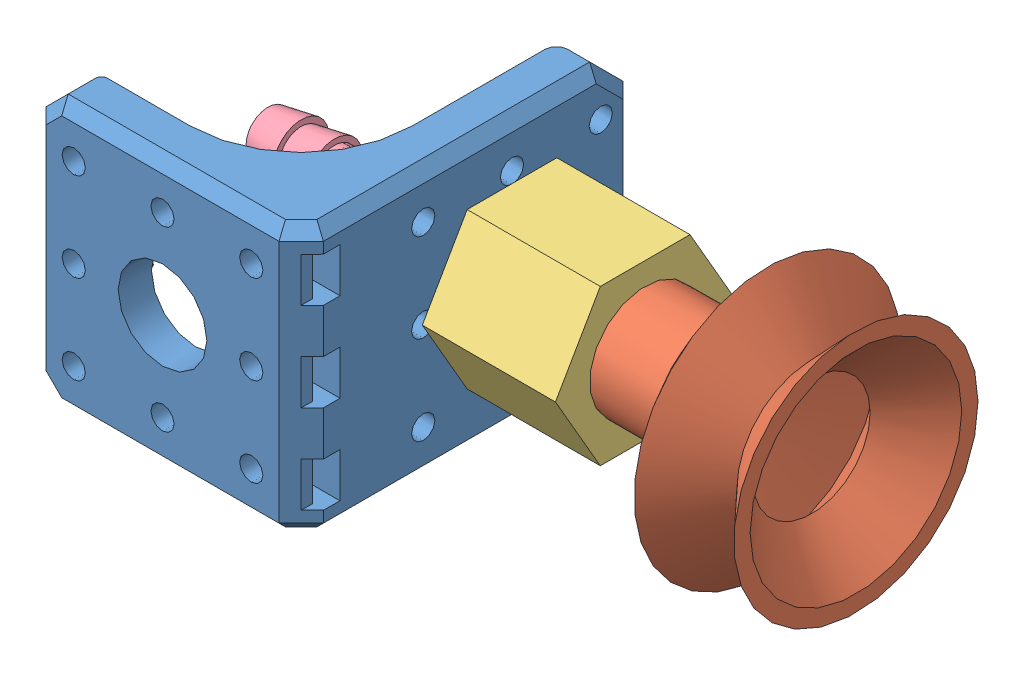
SolidWorks assembly Assemblage1, configuration Défaut. Lengths in mm.
Overall size (55 24 31).
4 component instances, 4 part files, 6 mates.
Components (placement in the parent):
- F9ORG-1: F9ORG [Défaut] at (9.7054 -0.548 15) size (24 24 30)
- ventouse_coval_VSA22_M5-1: ventouse_coval_VSA22_M5 [Default] at (40.7054 -0.548 -4) x (0 1 0) z (0 0 1) size (24 19 24)
- Insert_Femelle_IF10A-1: Insert_Femelle_IF10A [Défaut] at (21.7054 -0.548 -4) x (0 1 0) z (0 0 1) size (14 20 16.17)
- cannule_male_TET1804-1: cannule_male_TET1804 [Défaut] at (6.7054 -0.548 -4) x (0 0.807712 -0.589577) z (0 0.589577 0.807712) size (12 28 13.86)
Mates (geometry in assembly coordinates):
- Coïncidente1: coincident anti-aligned: plane of ventouse_coval_VSA22_M5-1 through (21.7054 4.452 -4) normal (-1 0 0); plane of Insert_Femelle_IF10A-1 through (21.7054 -0.548 -12.0829) normal (1 0 0)
- Coaxiale1: concentric anti-aligned: cylinder of ventouse_coval_VSA22_M5-1; cylinder of Insert_Femelle_IF10A-1
- Coaxiale2: concentric anti-aligned: cylinder of F9ORG-1; cylinder of Insert_Femelle_IF10A-1
- Coïncidente2: coincident anti-aligned: plane of F9ORG-1 through (9.7054 -12.548 15) normal (1 0 0); plane of Insert_Femelle_IF10A-1 through (9.7054 -0.548 -12.0829) normal (-1 0 0)
- Coaxiale3: concentric aligned: cylinder of ?; cylinder of Insert_Femelle_IF10A-1
- Distance1: distance = 3 mm aligned: plane of cannule_male_TET1804-1 through (6.7054 -4.6327 -9.596) normal (1 0 0); plane of F9ORG-1 through (9.7054 -12.548 15) normal (1 0 0)
